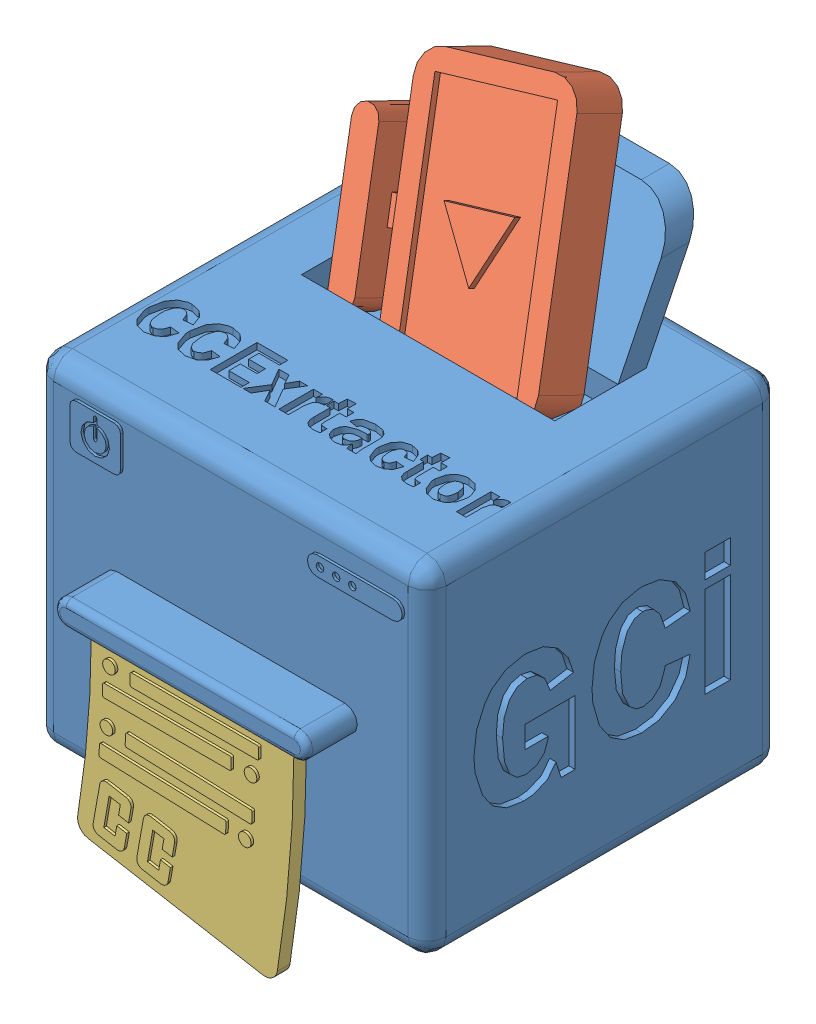
SolidWorks assembly [A] Static-Single Color, configuration Default. Lengths in mm.
Overall size (393.7 595.52 406.4).
3 component instances, 3 part files, 5 mates.
Components (placement in the parent):
- [P] Static-Single Color-Main Body-1: [P] Static-Single Color-Main Body [Default] at (117.5646 12.9468 186.1891) size (393.7 469.9 406.4)
- [P] Static-Single Color - TV-1: [P] Static-Single Color - TV [Default] at (9.8359 385.8522 265.6254) x (0.238662 -0.871606 0.428187) z (-0.971103 -0.214209 0.105233) size (254 50.8 203.2)
- [P] Static-Single Color - Script-1: [P] Static-Single Color - Script [Default] at (117.5646 178.0468 567.1891) x (1 0 0) z (0 -1 0) size (217.08 15.24 213.82)
Mates (geometry in assembly coordinates):
- Coincident1: coincident anti-aligned: plane of [P] Static-Single Color-Main Body-1 through (244.5646 355.8468 280.3659) normal (0 0.440929 0.897542); plane of [P] Static-Single Color - TV-1 through (9.8359 385.8522 265.6254) normal (0 -0.440929 -0.897542)
- Coincident2: coincident anti-aligned: plane of [P] Static-Single Color-Main Body-1 through (3.2646 178.0468 592.5891) normal (0 -1 0); plane of [P] Static-Single Color - Script-1 through (15.9646 178.0468 579.8891) normal (0 1 0)
- Parallel1: parallel aligned: plane of [P] Static-Single Color-Main Body-1 through (3.2646 190.7468 592.5891) normal (0 0 1); plane of [P] Static-Single Color - Script-1 through (-1022.0334 178.0468 579.8891) normal (0 0 1)
- Symmetric1: symmetric aligned: plane of [P] Static-Single Color-Main Body-1 through (314.4146 355.8468 541.7891) normal (1 0 0); plane of [P] Static-Single Color-Main Body-1 through (-79.2854 355.8468 541.7891) normal (-1 0 0); plane of [P] Static-Single Color - Script-1 through (117.5646 178.0468 567.1891) normal (1 0 0)
- Distance1: distance = 12.7 mm aligned: plane of [P] Static-Single Color - Script-1 through (-1022.0334 178.0468 579.8891) normal (0 0 1); plane of [P] Static-Single Color-Main Body-1 through (3.2646 190.7468 592.5891) normal (0 0 1)
